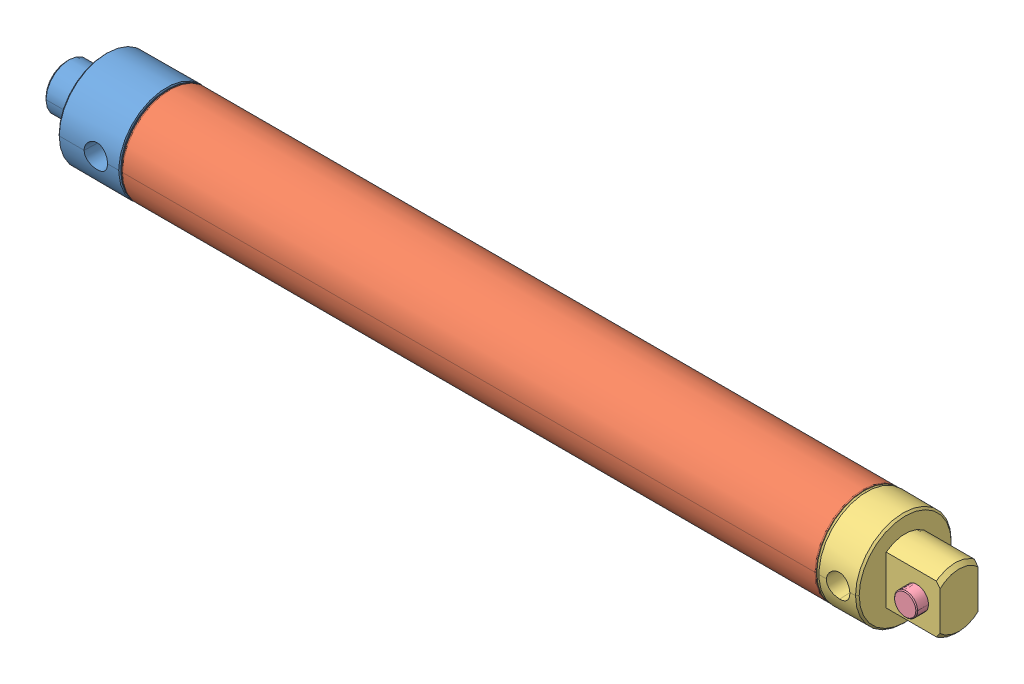
SolidWorks assembly 1710_DP_NOPISTON, configuration Default. Lengths in mm.
Overall size (368.43 39.54 39.61).
4 component instances, 4 part files, 0 mates.
Components (placement in the parent):
- _17R000_0_rod_guide_4-1: _17R000_0_rod_guide_4 [Default] at origin size (47.63 39.54 39.54)
- _17R_11_30250C_6-1: _17R_11_30250C_6 [Default] at (42.2275 0 0) size (288.92 39.54 39.54)
- _17P0000_rear_head_8-1: _17P0000_rear_head_8 [Default] at (323.977 0 0) size (44.45 39.54 39.61)
- _D_358_10-1: _D_358_10 [Default] at (358.902 0 0) x (1 0 0) z (0 0 -1) size (9.53 9.53 25.4)
